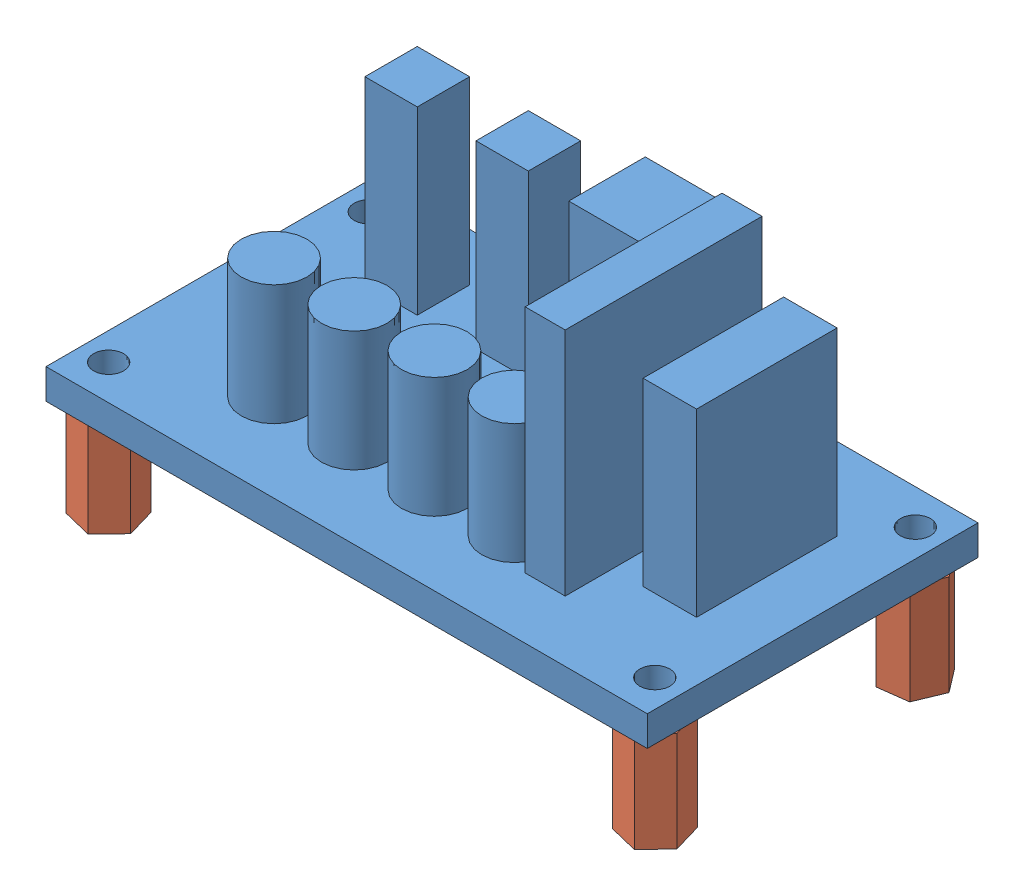
SolidWorks assembly carte_hacheur_entretoise, configuration Default. Lengths in mm.
Overall size (61.38 36 33.37).
5 component instances, 2 part files, 8 mates.
Components (placement in the parent):
- carte_hacheur-1: carte_hacheur [Default] at (-39.4629 -5.5333 16.4207) size (60 26 33)
- entretoise_M3_L10-1: entretoise_M3_L10 [Default] at (17.7871 -15.5333 -13.0793) x (0.923304 0 0.38407) z (-0.38407 0 0.923304) size (5.2 10 6)
- entretoise_M3_L10-2: entretoise_M3_L10 [Default] at (17.7871 -15.5333 12.9207) x (0.960063 0 -0.279785) z (0.279785 0 0.960063) size (5.2 10 6)
- entretoise_M3_L10-3: entretoise_M3_L10 [Default] at (-36.7129 -15.5333 12.9207) x (0.960063 0 -0.279785) z (0.279785 0 0.960063) size (5.2 10 6)
- entretoise_M3_L10-4: entretoise_M3_L10 [Default] at (-36.7129 -15.5333 -13.0793) x (0.960063 0 -0.279785) z (0.279785 0 0.960063) size (5.2 10 6)
Mates (geometry in assembly coordinates):
- Coaxiale1: concentric: cylinder of carte_hacheur-1 through (17.7871 -2.5333 -13.0793) axis (0 -1 0) radius 1.5; cylinder of entretoise_M3_L10-1 through (17.7871 -13.3743 -13.0793) axis (0 -1 0) radius 1.5
- Coaxiale2: concentric: cylinder of carte_hacheur-1 through (-36.7129 -2.5333 12.9207) axis (0 -1 0) radius 1.5; cylinder of entretoise_M3_L10-3 through (-36.7129 -15.8333 12.9207) axis (0 -1 0) radius 1.5
- Coaxiale3: concentric: cylinder of carte_hacheur-1 through (-36.7129 -2.5333 -13.0793) axis (0 -1 0) radius 1.5; cylinder of entretoise_M3_L10-4 through (-36.7129 -11.5727 -13.0793) axis (0 -1 0) radius 1.5
- Coaxiale4: concentric: cylinder of carte_hacheur-1 through (17.7871 -2.5333 12.9207) axis (0 -1 0) radius 1.5; cylinder of entretoise_M3_L10-2 through (17.7871 -20.3901 12.9207) axis (0 -1 0) radius 1.5
- Coïncidente1: coincident anti-aligned: plane of carte_hacheur-1 through (-39.4629 -5.5333 -16.5793) normal (0 -1 0); plane of entretoise_M3_L10-3 through (-37.5522 -5.5333 10.0405) normal (0 1 0)
- Coïncidente2: coincident anti-aligned: plane of carte_hacheur-1 through (-39.4629 -5.5333 -16.5793) normal (0 -1 0); plane of entretoise_M3_L10-4 through (-37.5522 -11.5727 -15.9595) normal (0 1 0)
- Coïncidente3: coincident anti-aligned: plane of carte_hacheur-1 through (-39.4629 -5.5333 -16.5793) normal (0 -1 0); plane of entretoise_M3_L10-2 through (16.9478 -20.3901 10.0405) normal (0 1 0)
- Coïncidente4: coincident anti-aligned: plane of carte_hacheur-1 through (-39.4629 -5.5333 -16.5793) normal (0 -1 0); plane of entretoise_M3_L10-1
